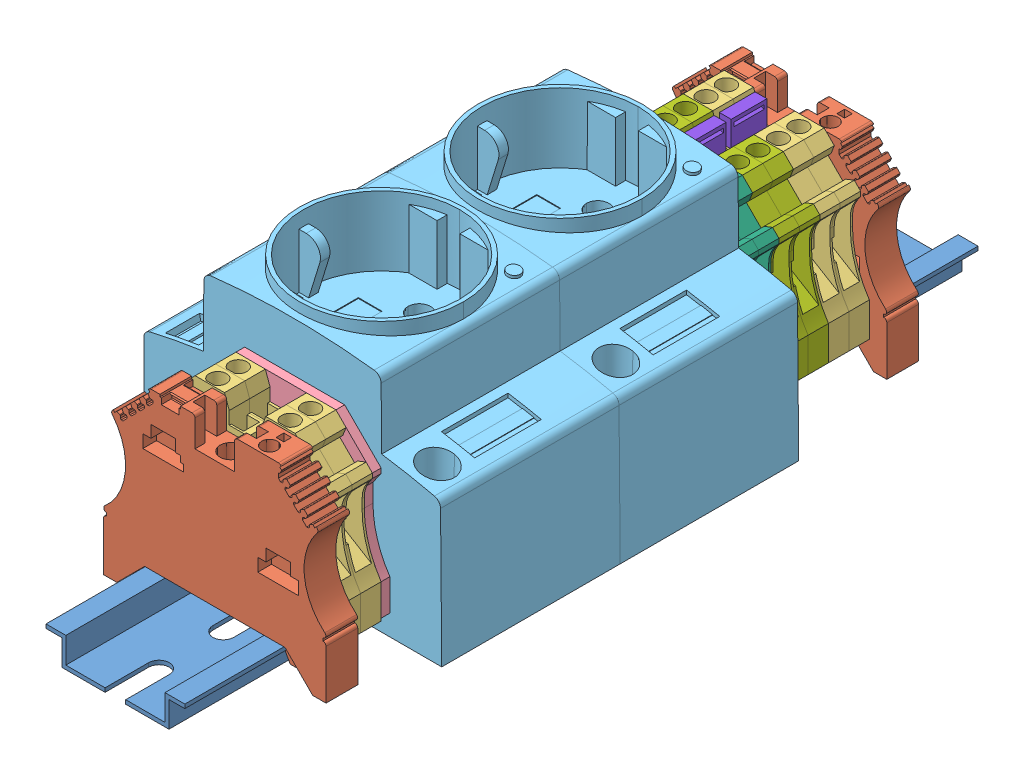
SolidWorks assembly Power Audio Schreibtisch, configuration Standard. Lengths in mm.
Overall size (75.48 67.56 200).
17 component instances, 8 part files, 51 mates.
Components (placement in the parent):
- Hutschiene-1: Hutschiene [200] at (-17.5 -7.5 -200) size (35 7.5 200)
- WEW_35_2-1: WEW_35_2 [Standard] at (-45.49 -7 -33) x (0 0 1) z (0 1 0) size (8 56.1 46.5)
- UT_2.5-1: UT_2.5 [Standard] at (-48.9989 10.6178 -33) x (0.992546 -0.121869 0) z (0 0 1) size (49.27 50.96 5.15)
- UT_2.5-2: UT_2.5 [Standard] at (-48.9989 10.6178 -38.15) x (0.992546 -0.121869 0) z (0 0 1) size (49.27 50.96 5.15)
- D_UT_2.5_10-1: D_UT_2.5_10 [Standard] at (-46.7297 58.45 -45.5) size (47 39.8 2.2)
- EO_CF_UT_LED-1: EO_CF_UT_LED [Standard] at (-87.6914 -21.0563 -70.25) size (75.48 61.64 45)
- EO_CF_UT_LED-2: EO_CF_UT_LED [Standard] at (-87.6914 -21.0563 -115.25) size (75.48 61.64 45)
- UT_2.5_PE-1: UT_2.5_PE [Standard] at (-48.9989 10.6178 -135.5) x (0.992546 -0.121869 0) z (0 0 1) size (49.27 50.96 5.15)
- UT_2.5_PE-2: UT_2.5_PE [Standard] at (-48.9989 10.6178 -140.65) x (0.992546 -0.121869 0) z (0 0 1) size (49.27 50.96 5.15)
- UT_2.5_BU-1: UT_2.5_BU [Standard] at (-48.9989 10.6178 -145.8) x (0.992546 -0.121869 0) z (0 0 1) size (49.27 50.96 5.15)
- UT_2.5_BU-2: UT_2.5_BU [Standard] at (-48.9989 10.6178 -150.95) x (0.992546 -0.121869 0) z (0 0 1) size (49.27 50.96 5.15)
- UT_2.5-3: UT_2.5 [Standard] at (-48.9989 10.6178 -156.1) x (0.992546 -0.121869 0) z (0 0 1) size (49.27 50.96 5.15)
- UT_2.5-4: UT_2.5 [Standard] at (-48.9989 10.6178 -161.25) x (0.992546 -0.121869 0) z (0 0 1) size (49.27 50.96 5.15)
- WEW_35_2-2: WEW_35_2 [Standard] at (-45.49 -7 -174.4) x (0 0 1) z (0 1 0) size (8 56.1 46.5)
- FBS_2-5-1: FBS_2-5 [Standard] at (-24.4072 49.175 -194.335) size (3 22.98 9)
- FBS_2-5-2: FBS_2-5 [Standard] at (-24.4072 49.175 -204.635) size (3 22.98 9)
- FBS_2-5-3: FBS_2-5 [Standard] at (-24.4072 49.175 -214.935) size (3 22.98 9)
Mates (geometry in assembly coordinates):
- Deckungsgleich1: coincident aligned: plane of Hutschiene-1 through (-17.5 -7.5 0) normal (0 0 1); plane of assembly through (0 0 0) normal (0 0 1)
- Deckungsgleich2: coincident aligned: plane of Hutschiene-1 through (0 -1 0) normal (1 0 0); plane of assembly through (0 0 0) normal (1 0 0)
- Deckungsgleich3: coincident aligned: plane of Hutschiene-1 through (-30 0 0) normal (0 1 0); plane of assembly through (0 0 0) normal (0 1 0)
- Deckungsgleich4: coincident anti-aligned: plane of Hutschiene-1 through (0 0 0) normal (0 1 0); plane of WEW_35_2-1 through (0.26 0 -25) normal (0 -1 0)
- Tangential2: tangent anti-aligned: cylinder of WEW_35_2-1 through (-37 -1.4 -29) axis (0 0 1) radius 2; plane of Hutschiene-1 through (-35 0 0) normal (-1 0 0)
- Deckungsgleich8: coincident anti-aligned: plane of Hutschiene-1 through (-30 0 0) normal (0 1 0); plane of UT_2.5-1 through (-8 0 -33) normal (0 -1 0)
- Deckungsgleich9: coincident anti-aligned: plane of Hutschiene-1 through (-30 0 0) normal (0 1 0); plane of UT_2.5-2 through (-8 0 -38.15) normal (0 -1 0)
- Deckungsgleich10: coincident anti-aligned: plane of Hutschiene-1 through (-35 0 0) normal (-1 0 0); plane of UT_2.5-2 through (-35 -0.3 -38.15) normal (1 0 0)
- Deckungsgleich11: coincident anti-aligned: plane of Hutschiene-1 through (-35 0 0) normal (-1 0 0); plane of UT_2.5-1 through (-35 -0.3 -33) normal (1 0 0)
- Deckungsgleich12: coincident anti-aligned: plane of WEW_35_2-1 through (-17.44 0 -33) normal (0 0 -1); plane of UT_2.5-1 through (-0.3 0 -33) normal (0 0 1)
- Deckungsgleich13: coincident anti-aligned: plane of UT_2.5-1 through (-0.3 0 -38.15) normal (0 0 -1); plane of UT_2.5-2 through (-0.3 0 -38.15) normal (0 0 1)
- Deckungsgleich14: coincident anti-aligned: plane of UT_2.5-2 through (-0.3 0 -43.3) normal (0 0 -1); plane of D_UT_2.5_10-1 through (-31.6534 31.331 -43.3) normal (0 0 1)
- Deckungsgleich15: coincident aligned: plane of UT_2.5-2 through (-32.9741 37.4259 -38.15) normal (-0.707107 0.707107 0); plane of D_UT_2.5_10-1 through (-30.4 40 -44.4) normal (-0.707107 0.707107 0)
- Deckungsgleich16: coincident aligned: plane of UT_2.5-2 through (-30.4 40 -38.15) normal (0 1 0); plane of D_UT_2.5_10-1 through (-23 40 -43.9) normal (0 1 0)
- Deckungsgleich17: coincident anti-aligned: plane of D_UT_2.5_10-1 through (8.626 -3.78 -45.5) normal (0 0 -1); plane of EO_CF_UT_LED-1 through (-18.35 2.45 -45.5) normal (0 0 1)
- Deckungsgleich18: coincident anti-aligned: plane of EO_CF_UT_LED-1 through (-18.35 2.45 -90.5) normal (0 0 -1); plane of EO_CF_UT_LED-2 through (-18.35 2.45 -90.5) normal (0 0 1)
- Deckungsgleich19: coincident anti-aligned: plane of Hutschiene-1 through (0 0 0) normal (0 1 0); plane of EO_CF_UT_LED-1 through (-54.65 0 -72.4) normal (0 -1 0)
- Deckungsgleich20: coincident anti-aligned: plane of Hutschiene-1 through (0 0 0) normal (0 1 0); plane of EO_CF_UT_LED-2 through (-54.65 0 -117.4) normal (0 -1 0)
- Deckungsgleich21: coincident anti-aligned: plane of Hutschiene-1 through (-35 0 0) normal (-1 0 0); plane of EO_CF_UT_LED-2 through (-35 -41.451 -121.75) normal (1 0 0)
- Deckungsgleich22: coincident anti-aligned: plane of Hutschiene-1 through (-35 0 0) normal (-1 0 0); plane of EO_CF_UT_LED-1 through (-35 -41.451 -76.75) normal (1 0 0)
- Deckungsgleich23: coincident anti-aligned: plane of EO_CF_UT_LED-2 through (-18.35 2.45 -135.5) normal (0 0 -1); plane of UT_2.5_PE-1 through (-0.3 0 -135.5) normal (0 0 1)
- Deckungsgleich24: coincident anti-aligned: plane of UT_2.5_PE-1 through (-0.3 0 -140.65) normal (0 0 -1); plane of UT_2.5_PE-2 through (-0.3 0 -140.65) normal (0 0 1)
- Deckungsgleich25: coincident anti-aligned: plane of UT_2.5_PE-2 through (-0.3 0 -145.8) normal (0 0 -1); plane of UT_2.5_BU-1 through (-0.3 0 -145.8) normal (0 0 1)
- Deckungsgleich26: coincident anti-aligned: plane of UT_2.5_BU-1 through (-0.3 0 -150.95) normal (0 0 -1); plane of UT_2.5_BU-2 through (-0.3 0 -150.95) normal (0 0 1)
- Deckungsgleich27: coincident anti-aligned: plane of UT_2.5_BU-2 through (-0.3 0 -156.1) normal (0 0 -1); plane of UT_2.5-3 through (-0.3 0 -156.1) normal (0 0 1)
- Deckungsgleich28: coincident anti-aligned: plane of UT_2.5-3 through (-0.3 0 -161.25) normal (0 0 -1); plane of UT_2.5-4 through (-0.3 0 -161.25) normal (0 0 1)
- Deckungsgleich29: coincident anti-aligned: plane of UT_2.5-4 through (-0.3 0 -166.4) normal (0 0 -1); plane of WEW_35_2-2 through (-17.44 0 -166.4) normal (0 0 1)
- Deckungsgleich30: coincident anti-aligned: plane of Hutschiene-1 through (0 0 0) normal (0 1 0); plane of UT_2.5_PE-1 through (-8 0 -135.5) normal (0 -1 0)
- Deckungsgleich31: coincident anti-aligned: plane of Hutschiene-1 through (0 0 0) normal (0 1 0); plane of UT_2.5_PE-2 through (-8 0 -140.65) normal (0 -1 0)
- Deckungsgleich32: coincident anti-aligned: plane of Hutschiene-1 through (0 0 0) normal (0 1 0); plane of UT_2.5_BU-1 through (-8 0 -145.8) normal (0 -1 0)
- Deckungsgleich33: coincident anti-aligned: plane of Hutschiene-1 through (0 0 0) normal (0 1 0); plane of UT_2.5_BU-2 through (-8 0 -150.95) normal (0 -1 0)
- Deckungsgleich34: coincident anti-aligned: plane of Hutschiene-1 through (0 0 0) normal (0 1 0); plane of UT_2.5-3 through (-8 0 -156.1) normal (0 -1 0)
- Deckungsgleich35: coincident anti-aligned: plane of Hutschiene-1 through (0 0 0) normal (0 1 0); plane of UT_2.5-4 through (-8 0 -161.25) normal (0 -1 0)
- Deckungsgleich36: coincident anti-aligned: plane of Hutschiene-1 through (0 0 0) normal (0 1 0); plane of WEW_35_2-2 through (0.26 0 -166.4) normal (0 -1 0)
- Deckungsgleich37: coincident anti-aligned: plane of Hutschiene-1 through (-35 0 0) normal (-1 0 0); plane of UT_2.5_PE-1 through (-35 -0.3 -135.5) normal (1 0 0)
- Deckungsgleich38: coincident anti-aligned: plane of Hutschiene-1 through (-35 0 0) normal (-1 0 0); plane of UT_2.5_PE-2 through (-35 -0.3 -140.65) normal (1 0 0)
- Deckungsgleich39: coincident anti-aligned: plane of Hutschiene-1 through (-35 0 0) normal (-1 0 0); plane of UT_2.5_BU-1 through (-35 -0.3 -145.8) normal (1 0 0)
- Deckungsgleich40: coincident anti-aligned: plane of Hutschiene-1 through (-35 0 0) normal (-1 0 0); plane of UT_2.5_BU-2 through (-35 -0.3 -150.95) normal (1 0 0)
- Deckungsgleich41: coincident anti-aligned: plane of Hutschiene-1 through (-35 0 0) normal (-1 0 0); plane of UT_2.5-3 through (-35 -0.3 -156.1) normal (1 0 0)
- Deckungsgleich42: coincident anti-aligned: plane of Hutschiene-1 through (-35 0 0) normal (-1 0 0); plane of UT_2.5-4 through (-35 -0.3 -161.25) normal (1 0 0)
- Tangential3: tangent anti-aligned: plane of Hutschiene-1 through (-35 0 0) normal (-1 0 0); cylinder of WEW_35_2-2 through (-37 -1.4 -170.4) axis (0 0 1) radius 2
- Deckungsgleich43: coincident anti-aligned: plane of UT_2.5_PE-1 through (-18.65 21.85 -135.975) normal (0 0 -1); plane of FBS_2-5-1 through (-18.8 39.7 -135.975) normal (0 0 1)
- Deckungsgleich44: coincident anti-aligned: plane of UT_2.5_PE-1 through (-21.8 36.703 -135.5) normal (1 0 0); plane of FBS_2-5-1 through (-21.8 41.9423 -170.235) normal (-1 0 0)
- Deckungsgleich45: coincident anti-aligned: plane of UT_2.5_BU-1 through (-18.65 21.85 -146.275) normal (0 0 -1); plane of FBS_2-5-2 through (-18.8 39.7 -146.275) normal (0 0 1)
- Deckungsgleich46: coincident anti-aligned: plane of UT_2.5_BU-1 through (-21.8 36.703 -145.8) normal (1 0 0); plane of FBS_2-5-2 through (-21.8 41.9423 -180.535) normal (-1 0 0)
- Deckungsgleich47: coincident anti-aligned: plane of UT_2.5-3 through (-21.8 36.703 -156.1) normal (1 0 0); plane of FBS_2-5-3 through (-21.8 41.9423 -190.835) normal (-1 0 0)
- Deckungsgleich48: coincident anti-aligned: plane of UT_2.5-3 through (-18.65 21.85 -156.575) normal (0 0 -1); plane of FBS_2-5-3 through (-18.8 39.7 -156.575) normal (0 0 1)
- Deckungsgleich49: coincident aligned: plane of UT_2.5-3 through (-30.4 40 -156.1) normal (0 1 0); plane of FBS_2-5-1 through (-18.8 40 -115.475) normal (0 1 0)
- Deckungsgleich50: coincident aligned: plane of UT_2.5-3 through (-30.4 40 -156.1) normal (0 1 0); plane of FBS_2-5-3 through (-18.8 40 -136.075) normal (0 1 0)
- Deckungsgleich51: coincident aligned: plane of UT_2.5_BU-1 through (-30.4 40 -145.8) normal (0 1 0); plane of FBS_2-5-2 through (-18.8 40 -125.775) normal (0 1 0)
- Abstand1: distance = 25 mm aligned: plane of WEW_35_2-1 through (-17.44 0 -25) normal (0 0 1); plane of Hutschiene-1 through (-17.5 -7.5 0) normal (0 0 1)
